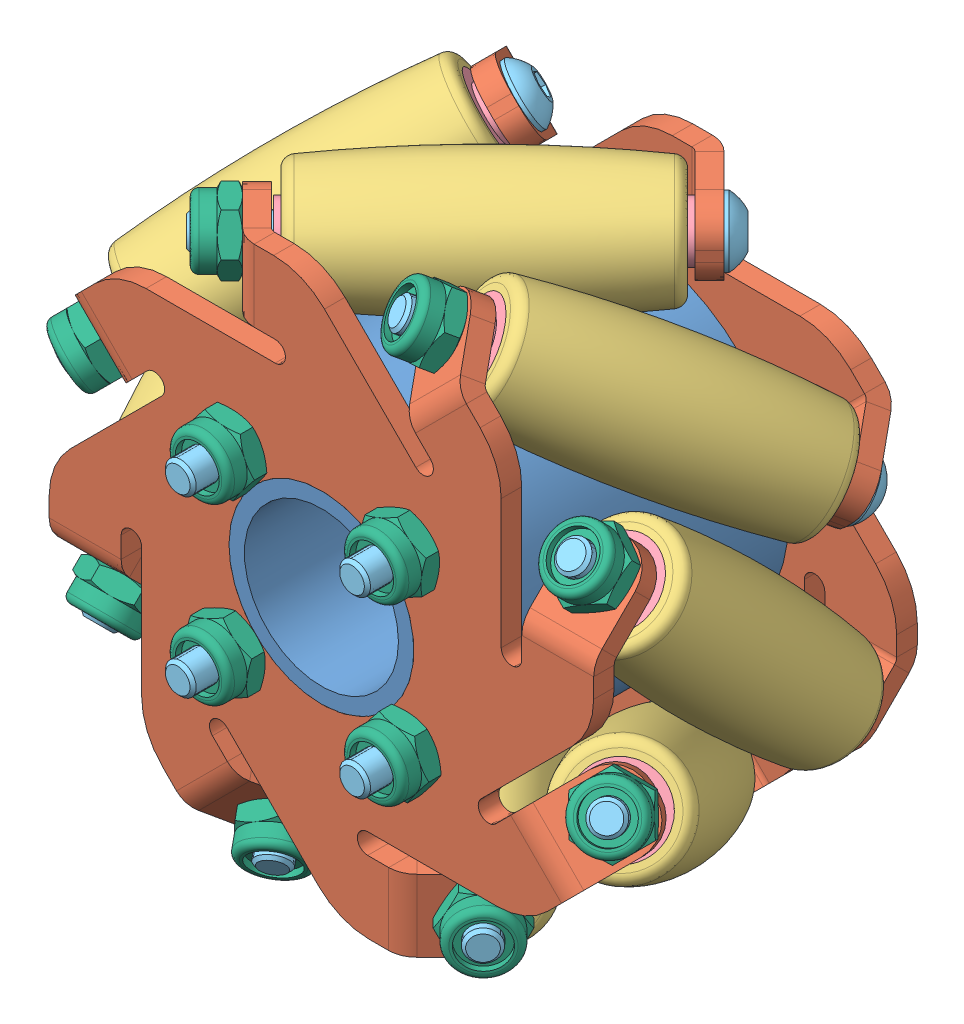
SolidWorks assembly mecanum wheel assembly, configuration Default. Lengths in mm.
Overall size (102.2 102.2 64.43).
51 component instances, 6 part files, 20 mates.
Components (placement in the parent):
- 3.shaft-1: 3.shaft [Default] at (-45.6858 23.4322 30.452) size (53.34 53.34 52.51)
- 1.frame-1: 1.frame [Default] at (-45.6858 23.4322 39.6232) x (-1 0 0) z (0 0 -1) size (91.71 91.71 12.64)
- 1.frame-2: 1.frame [Default] at (-45.6858 23.4322 -6.2193) x (-1 0 0) z (0 0 1) size (91.71 91.71 12.64)
- 2.roller-1: 2.roller [Default] at (-84.0268 23.5333 16.638) x (0 -0.707107 0.707107) z (0.983638 0.127391 0.127391) size (46.68 20 20)
- 4.roller_bracket-1: 4.roller_bracket [Default] at (-84.0268 39.7299 0.4414) x (-0.383049 0.653174 0.653174) z (-0.923728 -0.270857 -0.270857) size (12.5 3.33 12.5)
- 4.roller_bracket-2: 4.roller_bracket [Default] at (-84.0268 7.3367 32.8346) x (0.850043 -0.372442 -0.372442) z (-0.526713 -0.601071 -0.601071) size (12.5 3.33 12.5)
- 5.bolt-2: 5.bolt [Default] at (-84.0268 36.2864 3.8849) x (0 -0.707107 0.707107) z (-0.604734 0.56316 0.56316) size (64.43 9.5 9.5)
- torque nut 08_iso-1: torque nut 08_iso [ISO 10511-M6-N] at (-84.0268 1.8311 38.2658) x (1 0 0) z (0 -0.707107 0.707107) size (10 11.55 6)
- 4.roller_bracket-3: 4.roller_bracket [Default] at (-84.3212 7.8452 0.4414) x (-0.732721 0.191007 0.653174) z (-0.46165 -0.844699 -0.270857) size (12.5 3.33 12.5)
- 4.roller_bracket-4: 4.roller_bracket [Default] at (-61.9835 -14.9088 0.4414) x (-0.653174 -0.383049 0.653174) z (0.270857 -0.923728 -0.270857) size (12.5 3.33 12.5)
- 4.roller_bracket-5: 4.roller_bracket [Default] at (-30.0988 -15.2032 0.4414) x (-0.191007 -0.732721 0.653174) z (0.844699 -0.46165 -0.270857) size (12.5 3.33 12.5)
- 4.roller_bracket-6: 4.roller_bracket [Default] at (-7.3448 7.1345 0.4414) x (0.383049 -0.653174 0.653174) z (0.923728 0.270857 -0.270857) size (12.5 3.33 12.5)
- 4.roller_bracket-7: 4.roller_bracket [Default] at (-7.0504 39.0192 0.4414) x (0.732721 -0.191007 0.653174) z (0.46165 0.844699 -0.270857) size (12.5 3.33 12.5)
- 4.roller_bracket-8: 4.roller_bracket [Default] at (-29.3881 61.7732 0.4414) x (0.653174 0.383049 0.653174) z (-0.270857 0.923728 -0.270857) size (12.5 3.33 12.5)
- 4.roller_bracket-9: 4.roller_bracket [Default] at (-61.2728 62.0676 0.4414) x (0.191007 0.732721 0.653174) z (-0.844699 0.46165 -0.270857) size (12.5 3.33 12.5)
- 2.roller-2: 2.roller [Default] at (-72.8685 -3.6075 16.638) x (0.5 -0.5 0.707107) z (0.605458 0.785616 0.127391) size (46.68 20 20)
- 2.roller-3: 2.roller [Default] at (-45.7869 -14.9088 16.638) x (0.707107 0 0.707107) z (-0.127391 0.983638 0.127391) size (46.68 20 20)
- 2.roller-4: 2.roller [Default] at (-18.6461 -3.7505 16.638) x (0.5 0.5 0.707107) z (-0.785616 0.605458 0.127391) size (46.68 20 20)
- 2.roller-5: 2.roller [Default] at (-7.3448 23.3311 16.638) x (0 0.707107 0.707107) z (-0.983638 -0.127391 0.127391) size (46.68 20 20)
- 2.roller-6: 2.roller [Default] at (-18.5031 50.4719 16.638) x (-0.5 0.5 0.707107) z (-0.605458 -0.785616 0.127391) size (46.68 20 20)
- 2.roller-7: 2.roller [Default] at (-45.5847 61.7732 16.638) x (-0.707107 0 0.707107) z (0.127391 -0.983638 0.127391) size (46.68 20 20)
- 2.roller-8: 2.roller [Default] at (-72.7255 50.6149 16.638) x (-0.5 -0.5 0.707107) z (0.785616 -0.605458 0.127391) size (46.68 20 20)
- 4.roller_bracket-10: 4.roller_bracket [Default] at (-61.4158 -15.0602 32.8346) x (0.864428 0.337715 -0.372442) z (0.052579 -0.797464 -0.601071) size (12.5 3.33 12.5)
- 4.roller_bracket-11: 4.roller_bracket [Default] at (-29.5903 -14.9088 32.8346) x (0.372442 0.850043 -0.372442) z (0.601071 -0.526713 -0.601071) size (12.5 3.33 12.5)
- 4.roller_bracket-12: 4.roller_bracket [Default] at (-7.1934 7.7022 32.8346) x (-0.337715 0.864428 -0.372442) z (0.797464 0.052579 -0.601071) size (12.5 3.33 12.5)
- 4.roller_bracket-13: 4.roller_bracket [Default] at (-7.3448 39.5276 32.8346) x (-0.850043 0.372442 -0.372442) z (0.526713 0.601071 -0.601071) size (12.5 3.33 12.5)
- 4.roller_bracket-14: 4.roller_bracket [Default] at (-29.9558 61.9246 32.8346) x (-0.864428 -0.337715 -0.372442) z (-0.052579 0.797464 -0.601071) size (12.5 3.33 12.5)
- 4.roller_bracket-15: 4.roller_bracket [Default] at (-61.7812 61.7732 32.8346) x (-0.372442 -0.850043 -0.372442) z (-0.601071 0.526713 -0.601071) size (12.5 3.33 12.5)
- 4.roller_bracket-16: 4.roller_bracket [Default] at (-84.1782 39.1622 32.8346) x (0.337715 -0.864428 -0.372442) z (-0.797464 -0.052579 -0.601071) size (12.5 3.33 12.5)
- 5.bolt-3: 5.bolt [Default] at (-81.8863 5.4103 3.8849) x (0.5 -0.5 0.707107) z (-0.825825 -0.029397 0.56316) size (64.43 9.5 9.5)
- 5.bolt-4: 5.bolt [Default] at (-58.54 -14.9088 3.8849) x (0.707107 0 0.707107) z (-0.56316 -0.604734 0.56316) size (64.43 9.5 9.5)
- 5.bolt-5: 5.bolt [Default] at (-27.6639 -12.7683 3.8849) x (0.5 0.5 0.707107) z (0.029397 -0.825825 0.56316) size (64.43 9.5 9.5)
- 5.bolt-6: 5.bolt [Default] at (-7.3448 10.578 3.8849) x (0 0.707107 0.707107) z (0.604734 -0.56316 0.56316) size (64.43 9.5 9.5)
- 5.bolt-7: 5.bolt [Default] at (-9.4853 41.4541 3.8849) x (-0.5 0.5 0.707107) z (0.825825 0.029397 0.56316) size (64.43 9.5 9.5)
- 5.bolt-8: 5.bolt [Default] at (-32.8316 61.7732 3.8849) x (-0.707107 0 0.707107) z (0.56316 0.604734 0.56316) size (64.43 9.5 9.5)
- 5.bolt-9: 5.bolt [Default] at (-63.7077 59.6327 3.8849) x (-0.5 -0.5 0.707107) z (-0.029397 0.825825 0.56316) size (64.43 9.5 9.5)
- torque nut 08_iso-2: torque nut 08_iso [ISO 10511-M6-N] at (-57.5227 -18.9532 38.2658) x (0.707107 0.707107 0) z (0.5 -0.5 0.707107) size (10 11.55 6)
- torque nut 08_iso-3: torque nut 08_iso [ISO 10511-M6-N] at (-24.0847 -14.9088 38.2658) x (0 1 0) z (0.707107 0 0.707107) size (10 11.55 6)
- torque nut 08_iso-4: torque nut 08_iso [ISO 10511-M6-N] at (-3.3004 11.5953 38.2658) x (-0.707107 0.707107 0) z (0.5 0.5 0.707107) size (10 11.55 6)
- torque nut 08_iso-5: torque nut 08_iso [ISO 10511-M6-N] at (-7.3448 45.0332 38.2658) x (-1 0 0) z (0 0.707107 0.707107) size (10 11.55 6)
- torque nut 08_iso-6: torque nut 08_iso [ISO 10511-M6-N] at (-33.8489 65.8176 38.2658) x (-0.707107 -0.707107 0) z (-0.5 0.5 0.707107) size (10 11.55 6)
- torque nut 08_iso-7: torque nut 08_iso [ISO 10511-M6-N] at (-67.2868 61.7732 38.2658) x (0 -1 0) z (-0.707107 0 0.707107) size (10 11.55 6)
- torque nut 08_iso-8: torque nut 08_iso [ISO 10511-M6-N] at (-88.0712 35.2691 38.2658) x (0.707107 -0.707107 0) z (-0.5 -0.5 0.707107) size (10 11.55 6)
- 5.bolt-10: 5.bolt [Default] at (-31.5408 37.5772 -0.0834) x (0 0 1) z (-0.509821 0.86028 0) size (64.43 9.5 9.5)
- torque nut 08_iso-9: torque nut 08_iso [ISO 10511-M6-N] at (-31.5408 37.5772 45.8572) x (0.993457 -0.114205 0) z (0 0 1) size (10 11.55 6)
- 5.bolt-12: 5.bolt [Default] at (-59.8308 37.5772 -0.0834) x (0 0 1) z (-0.86028 -0.509821 0) size (64.43 9.5 9.5)
- 5.bolt-13: 5.bolt [Default] at (-59.8308 9.2872 -0.0834) x (0 0 1) z (0.509821 -0.86028 0) size (64.43 9.5 9.5)
- 5.bolt-14: 5.bolt [Default] at (-31.5408 9.2872 -0.0834) x (0 0 1) z (0.86028 0.509821 0) size (64.43 9.5 9.5)
- torque nut 08_iso-11: torque nut 08_iso [ISO 10511-M6-N] at (-59.8308 37.5772 45.8572) x (0.114205 0.993457 0) z (0 0 1) size (10 11.55 6)
- torque nut 08_iso-12: torque nut 08_iso [ISO 10511-M6-N] at (-59.8308 9.2872 45.8572) x (-0.993457 0.114205 0) z (0 0 1) size (10 11.55 6)
- torque nut 08_iso-13: torque nut 08_iso [ISO 10511-M6-N] at (-31.5408 9.2872 45.8572) x (-0.114205 -0.993457 0) z (0 0 1) size (10 11.55 6)
Mates (geometry in assembly coordinates):
- Concentric1: concentric anti-aligned: cylinder of 3.shaft-1 through (-45.6858 23.4322 -6.2193) axis (0 0 1) radius 12.5025; cylinder of 1.frame-1 through (-45.6858 23.4322 42.9572) axis (0 0 -1) radius 15.003
- Coincident1: coincident anti-aligned: plane of 3.shaft-1 through (-45.6858 23.4322 39.6232) normal (0 0 1); plane of 1.frame-1 through (-53.4386 55.9387 39.6232) normal (0 0 -1)
- Concentric2: concentric anti-aligned: cylinder of 3.shaft-1 through (-31.5408 37.5772 -38.7258) axis (0 0 1) radius 2.5005; cylinder of 1.frame-1 through (-31.5408 37.5772 42.9572) axis (0 0 -1) radius 2.5005
- Concentric3: concentric aligned: cylinder of 3.shaft-1 through (-45.6858 23.4322 -6.2193) axis (0 0 1) radius 12.5025; cylinder of 1.frame-2 through (-45.6858 23.4322 -9.5533) axis (0 0 1) radius 15.003
- Coincident2: coincident anti-aligned: plane of 3.shaft-1 through (-45.6858 23.4322 -6.2193) normal (0 0 -1); plane of 1.frame-2 through (-53.4386 -9.0743 -6.2193) normal (0 0 1)
- Concentric4: concentric aligned: cylinder of 3.shaft-1 through (-59.8308 9.2872 -38.7258) axis (0 0 1) radius 2.5005; cylinder of 1.frame-2 through (-59.8308 9.2872 -9.5533) axis (0 0 1) radius 2.5005
- Concentric6: concentric aligned: cylinder of 2.roller-1 through (-84.0268 39.6017 0.5696) axis (0 0.707107 -0.707107) radius 6.2512; cylinder of 4.roller_bracket-1 through (-84.0268 38.2676 1.9037) axis (0 0.707107 -0.707107) radius 6.2512
- Coincident3: coincident anti-aligned: plane of 2.roller-1 through (-83.5763 36.5284 0.1645) normal (0 0.707107 -0.707107); plane of 4.roller_bracket-1 through (-84.0268 38.2676 1.9037) normal (0 -0.707107 0.707107)
- Concentric8: concentric anti-aligned: cylinder of 2.roller-1 through (-84.0268 39.6017 0.5696) axis (0 0.707107 -0.707107) radius 6.2512; cylinder of 4.roller_bracket-2 through (-84.0268 8.799 31.3723) axis (0 -0.707107 0.707107) radius 6.2512
- Coincident4: coincident anti-aligned: plane of 2.roller-1 through (-83.5763 7.0598 29.6332) normal (0 -0.707107 0.707107); plane of 4.roller_bracket-2 through (-84.0268 8.799 31.3723) normal (0 0.707107 -0.707107)
- Concentric9: concentric anti-aligned: cylinder of 1.frame-2 through (-84.0268 42.9826 -2.8113) axis (0 -0.707107 0.707107) radius 2.5005; cylinder of 2.roller-1 through (-84.0268 39.6017 0.5696) axis (0 0.707107 -0.707107) radius 2.5005
- Coincident5: coincident anti-aligned: plane of 1.frame-2 through (-53.4386 2.9052 -38.1737) normal (0 -0.707107 0.707107); plane of 4.roller_bracket-1 through (-84.0268 40.6251 -0.4538) normal (0 0.707107 -0.707107)
- Concentric10: concentric anti-aligned: cylinder of 2.roller-1 through (-84.0268 39.6017 0.5696) axis (0 0.707107 -0.707107) radius 2.5005; cylinder of 5.bolt-2 through (-84.0268 -0.631 40.8023) axis (0 -0.707107 0.707107) radius 2.5005
- Coincident6: coincident anti-aligned: plane of 1.frame-2 through (-53.4386 5.2627 -40.5312) normal (0 0.707107 -0.707107); plane of 5.bolt-2 through (-80.243 45.0142 -0.7798) normal (0 -0.707107 0.707107)
- Concentric11: concentric anti-aligned: cylinder of 1.frame-1 through (-84.0268 3.8818 36.2152) axis (0 0.707107 -0.707107) radius 2.5005; cylinder of torque nut 08_iso-1 through (-84.0268 -11.6392 51.7362) axis (0 -0.707107 0.707107) radius 3
- Coincident7: coincident anti-aligned: plane of 1.frame-1 through (-53.4386 41.6017 73.9351) normal (0 -0.707107 0.707107); plane of torque nut 08_iso-1 through (-84.0268 7.9642 40.2977) normal (0 0.707107 -0.707107)
- Concentric12: concentric aligned: cylinder of 1.frame-2 through (-31.5408 37.5772 -9.5533) axis (0 0 1) radius 2.5005; cylinder of 5.bolt-10 through (-31.5408 37.5772 52.1257) axis (0 0 1) radius 2.5005
- Coincident8: coincident anti-aligned: plane of 1.frame-2 through (-53.4386 -9.0743 -9.5533) normal (0 0 -1); plane of 5.bolt-10 through (-27.4537 39.9993 -9.5533) normal (0 0 1)
- Concentric13: concentric aligned: cylinder of 5.bolt-10 through (-31.5408 37.5772 52.1257) axis (0 0 1) radius 2.5005; cylinder of torque nut 08_iso-9 through (-31.5408 37.5772 64.9072) axis (0 0 1) radius 3
- Coincident9: coincident anti-aligned: plane of 1.frame-1 through (-53.4386 55.9387 42.9572) normal (0 0 1); plane of torque nut 08_iso-9 through (-30.8815 43.3129 42.9572) normal (0 0 -1)
